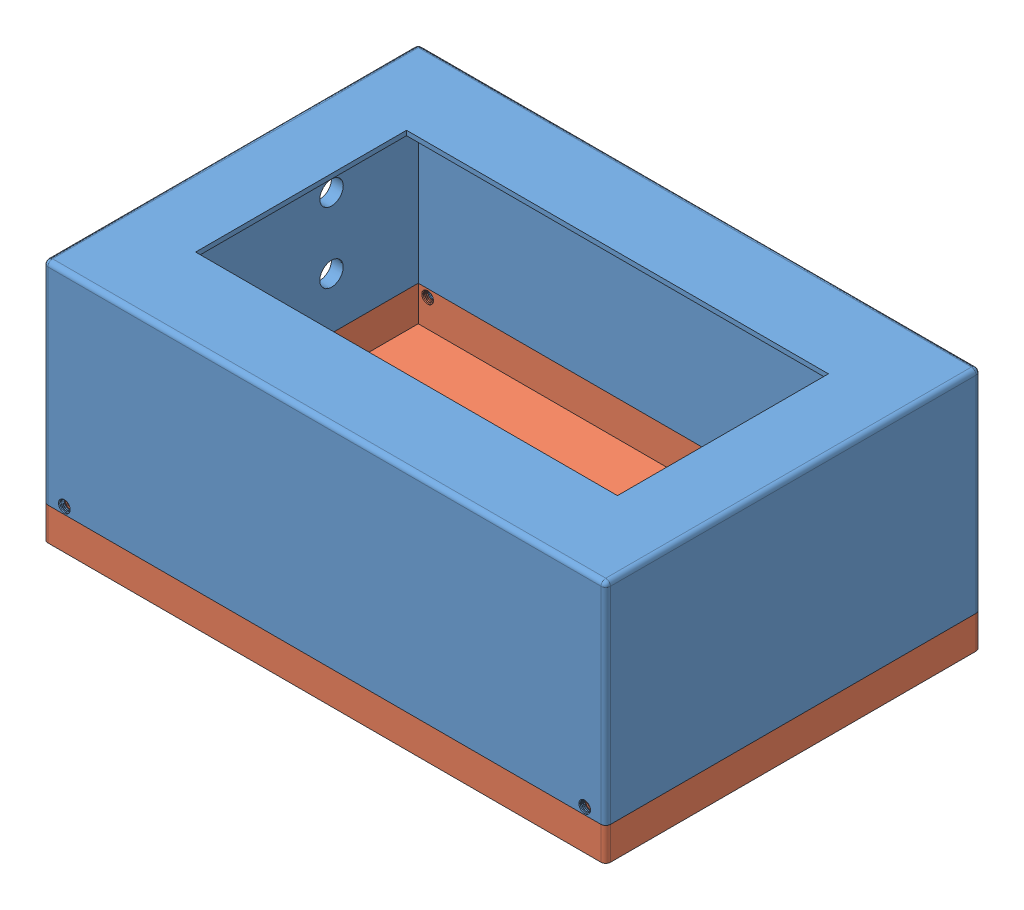
SolidWorks assembly Assem1, configuration Default. Lengths in mm.
Overall size (120.5 52 80.57).
2 component instances, 2 part files, 2 mates.
Components (placement in the parent):
- Part1-1: Part1 [Default] at (37.2461 56.4965 100.914) size (120.5 45 80.57)
- Part2-1: Part2 [Default] at (37.2461 54.4965 100.914) size (120 10 80)
Mates (geometry in assembly coordinates):
- Coincident1: coincident aligned: line of Part1-1 through (-21.7539 61.4965 140.914) axis (1 0 0); line of Part2-1 through (-21.7539 61.4965 140.914) axis (1 0 0)
- Coincident3: coincident anti-aligned: line of Part1-1 through (-22.7539 61.4965 139.914) axis (0 0 -1); line of Part2-1 through (-22.7539 61.4965 61.914) axis (0 0 1)
